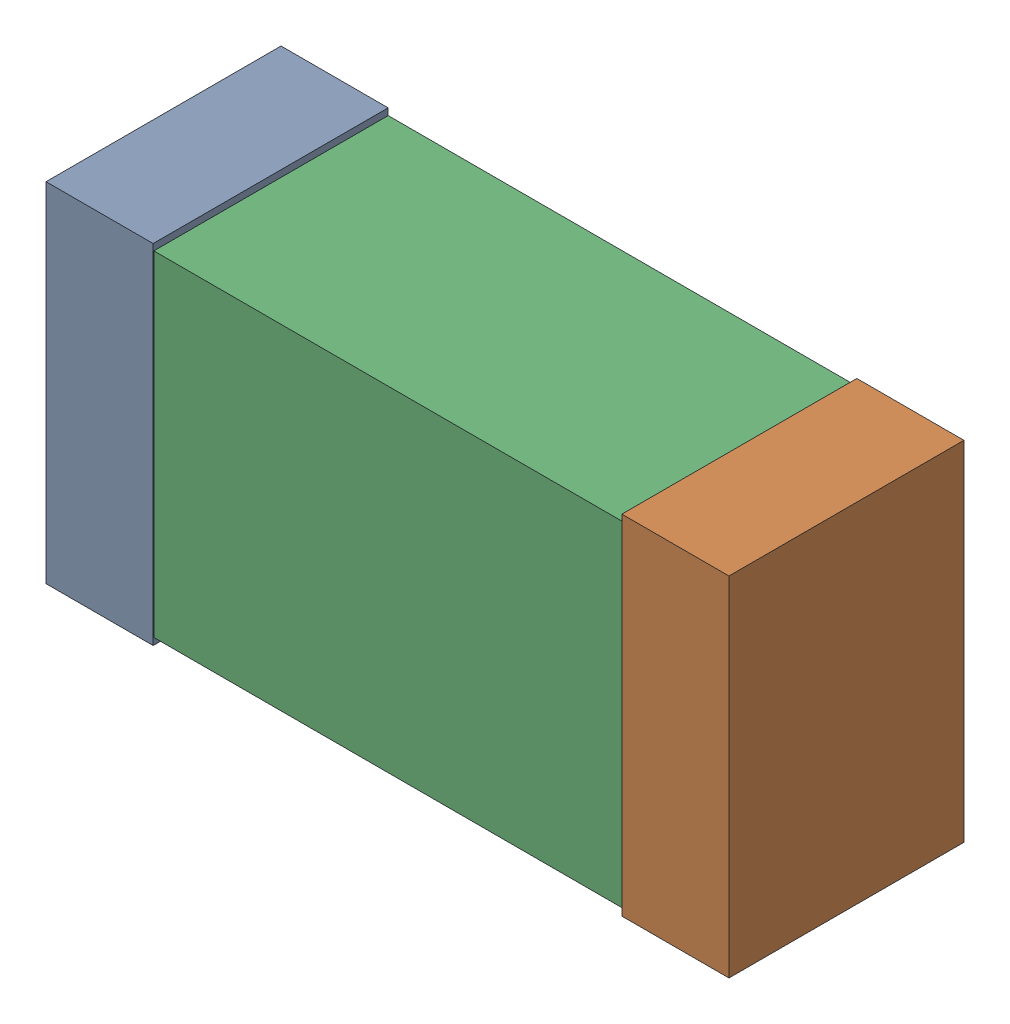
SolidWorks assembly R8, configuration Default. Lengths in mm.
Overall size (1.02 0.52 0.35).
6 component instances, 2 part files, 0 mates.
Components (placement in the parent):
- 870940480-1: 870940480 [Default] at (52.6298 27.4552 0) size (0.16 0.52 0.35)
  - Extruded-1: Extruded [Default] at origin size (0.16 0.52 0.35)
- 870940480-2: 870940480 [Default] at (53.4898 27.4552 0) size (0.16 0.52 0.35)
  - Extruded-1: Extruded [Default] at origin size (0.16 0.52 0.35)
- 870940640-1: 870940640 [Default] at (53.0598 27.4552 0) size (1 0.5 0.35)
  - Extruded_2-1: Extruded_2 [Default] at origin size (1 0.5 0.35)
